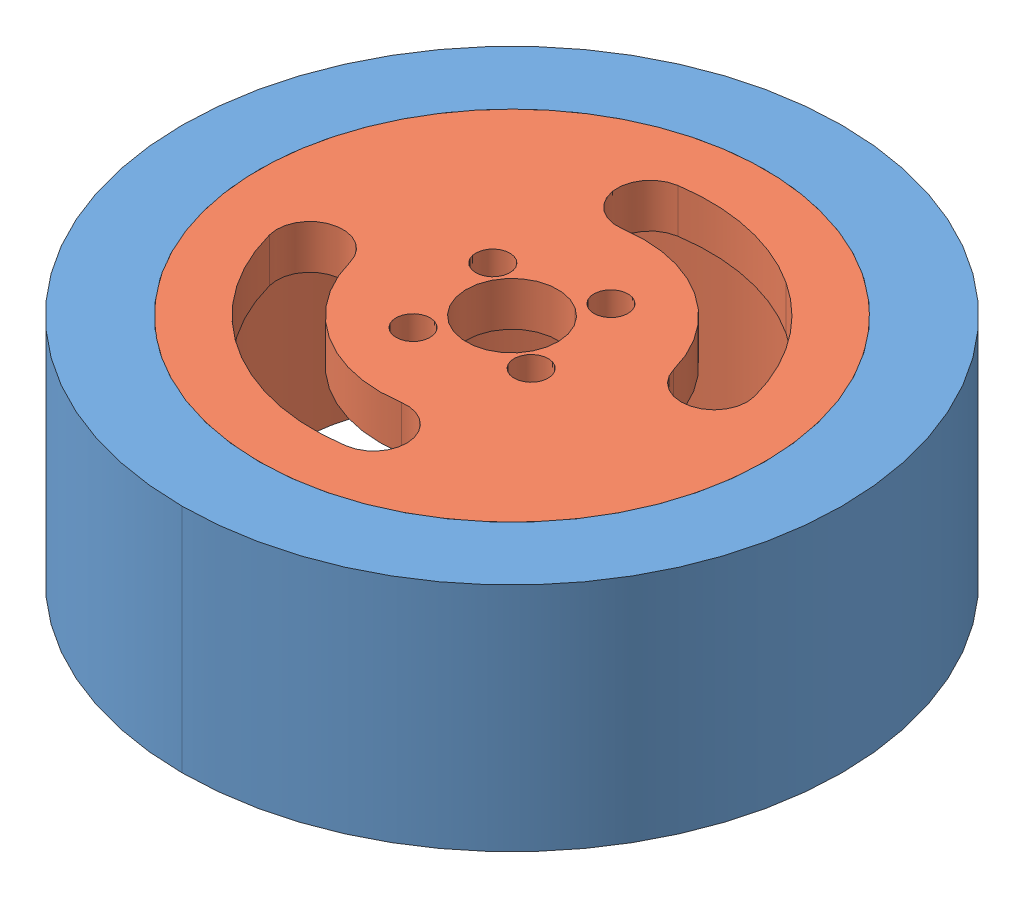
SolidWorks assembly 溪地直径60摩擦轮, configuration 默认. Lengths in mm.
Overall size (63.67 21 63.67).
3 component instances, 2 part files, 0 mates.
Components (placement in the parent):
- 摩擦轮（溪地）.STEP-1: 摩擦轮（溪地）.STEP [默认] at origin size (63.67 21 63.67)
  - __________________.STEP-1: __________________.STEP [默认] at (1.0474 -9.3308 145.5722) size (60 21 60)
  - ________________.STEP-1: ________________.STEP [默认] at (1.0474 11.6692 145.5722) x (-0.837169 0 -0.546944) z (-0.546944 0 0.837169) size (46 21 46)
